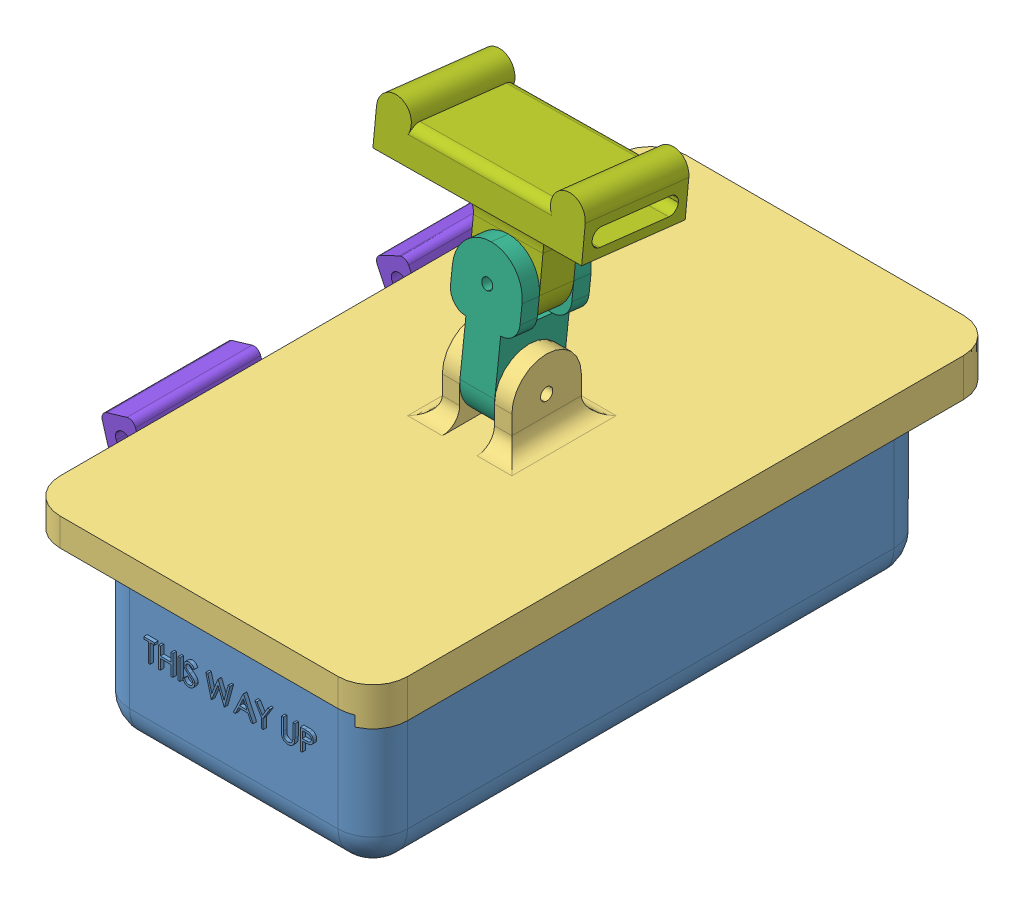
SolidWorks assembly Enclosure, configuration Default. Lengths in mm.
Overall size (141.75 176.14 228.6).
95 component instances, 26 part files, 36 mates.
Components (placement in the parent):
- Case-2: Case [Default] at (-101.6 0 -203.2) x (0 0 1) z (0 1 0) size (222.25 128.91 71.12)
- Battery Mockup-1: Battery Mockup [Default] at (-90.805 45.72 -177.165) x (0 0 1) z (-1 0 0) size (171.45 22.86 80.01)
- Lid-1: Lid [Default] at (12.7 73.66 12.7) x (-1 0 0) z (0 0 1) size (132.08 39.88 228.6)
- Camera Bracket-1: Camera Bracket [Default] at (-25.4 2.54 -66.675) x (0 0 -1) z (1 0 0) size (50.8 7.62 50.8)
- Separator-1: Separator [Default] at (-3.175 45.72 -3.175) x (0 -1 0) z (1 0 0) size (2.54 196.85 95.25)
- Cam V2.1 v1.step-1: Cam V2.1 v1.step [Default] at (-51.73 11.16 -89.4159) x (0 -1 0) z (1 0 0) size (6.48 24.01 25.01)
- RapberryPiZero.STEP-1: RapberryPiZero.STEP [Default] at (-102.4814 -13.0566 -128.6208) x (-1 0 0) z (0 0 -1) size (65 4.45 31.23)
  - Raspberry_pizero_PCB.STEP-1: Raspberry_pizero_PCB.STEP [Default] at (-51.2564 20.0966 13.0542) size (65 1 30)
  - Micro USB_input_female (short)-SMT.STEP-1: Micro USB_input_female (short)-SMT.STEP [Default] at (-42.3564 22.3216 26.5042) size (7.98 2.94 5.43)
  - Micro USB_input_female (short)-SMT.STEP-2: Micro USB_input_female (short)-SMT.STEP [Default] at (-29.7564 22.3216 26.5042) size (7.98 2.94 5.43)
  - 0204 - Capacitor.STEP-1: 0204 - Capacitor.STEP [Default] at (-62.4121 21.3466 11.2398) size (1 0.5 0.6)
  - 0204 - Capacitor.STEP-2: 0204 - Capacitor.STEP [Default] at (-62.4121 21.3466 12.2528) size (1 0.5 0.6)
  - 0204 - Capacitor.STEP-3: 0204 - Capacitor.STEP [Default] at (-61.8122 21.3466 13.3136) size (1 0.5 0.6)
  - 0204 - Capacitor.STEP-4: 0204 - Capacitor.STEP [Default] at (-61.8122 21.3466 14.2646) size (1 0.5 0.6)
  - 0204 - Capacitor.STEP-5: 0204 - Capacitor.STEP [Default] at (-61.8122 21.3466 15.241) size (1 0.5 0.6)
  - 0204 - Capacitor.STEP-6: 0204 - Capacitor.STEP [Default] at (-61.8122 21.3466 16.2144) size (1 0.5 0.6)
  - 0204 - Capacitor.STEP-7: 0204 - Capacitor.STEP [Default] at (-61.8122 21.3466 17.2416) size (1 0.5 0.6)
  - 0204 - Capacitor.STEP-8: 0204 - Capacitor.STEP [Default] at (-62.5919 21.3466 20.9695) size (1 0.5 0.6)
  - 0204 - Capacitor.STEP-9: 0204 - Capacitor.STEP [Default] at (-62.5919 21.3466 21.919) size (1 0.5 0.6)
  - 0204 - Capacitor.STEP-10: 0204 - Capacitor.STEP [Default] at (-60.4584 21.3466 22.3712) x (0 0 1) z (-1 0 0) size (1 0.5 0.6)
  - 0204 - Capacitor.STEP-11: 0204 - Capacitor.STEP [Default] at (-60.0807 21.3466 22.3712) x (0 0 -1) z (1 0 0) size (1 0.5 0.6)
  - 0204 - Capacitor.STEP-12: 0204 - Capacitor.STEP [Default] at (-59.0466 21.3466 22.3712) x (0 0 -1) z (1 0 0) size (1 0.5 0.6)
  - 0204 - Capacitor.STEP-13: 0204 - Capacitor.STEP [Default] at (-52.6496 21.3466 22.316) x (0 0 1) z (-1 0 0) size (1 0.5 0.6)
  - 0204 - Capacitor.STEP-14: 0204 - Capacitor.STEP [Default] at (-52.25 21.3466 22.316) x (0 0 -1) z (1 0 0) size (1 0.5 0.6)
  - 0204 - Capacitor.STEP-15: 0204 - Capacitor.STEP [Default] at (-51.2398 21.3466 22.316) x (0 0 -1) z (1 0 0) size (1 0.5 0.6)
  - 0204 - Capacitor.STEP-16: 0204 - Capacitor.STEP [Default] at (-49.1841 21.3466 22.316) x (0 0 -1) z (1 0 0) size (1 0.5 0.6)
  - 0204 - Capacitor.STEP-17: 0204 - Capacitor.STEP [Default] at (-48.1448 21.3466 22.316) x (0 0 -1) z (1 0 0) size (1 0.5 0.6)
  - 0204 - Capacitor.STEP-18: 0204 - Capacitor.STEP [Default] at (-46.475 21.3466 21.113) size (1 0.5 0.6)
  - 0204 - Capacitor.STEP-19: 0204 - Capacitor.STEP [Default] at (-45.7322 21.3466 20.0663) size (1 0.5 0.6)
  - 0204 - Capacitor.STEP-20: 0204 - Capacitor.STEP [Default] at (-45.7322 21.3466 19.0675) size (1 0.5 0.6)
  - 0204 - Capacitor.STEP-21: 0204 - Capacitor.STEP [Default] at (-45.7322 21.3466 18.1249) size (1 0.5 0.6)
  - 0204 - Capacitor.STEP-22: 0204 - Capacitor.STEP [Default] at (-45.7322 21.3466 17.1095) size (1 0.5 0.6)
  - 0204 - Capacitor.STEP-23: 0204 - Capacitor.STEP [Default] at (-46.3457 21.3466 16.1412) size (1 0.5 0.6)
  - 0204 - Capacitor.STEP-24: 0204 - Capacitor.STEP [Default] at (-46.3457 21.3466 15.1229) size (1 0.5 0.6)
  - 0204 - Capacitor.STEP-25: 0204 - Capacitor.STEP [Default] at (-46.3457 21.3466 14.0197) size (1 0.5 0.6)
  - 0204 - Capacitor.STEP-26: 0204 - Capacitor.STEP [Default] at (-46.3457 21.3466 12.9589) size (1 0.5 0.6)
  - 0204 - Capacitor.STEP-27: 0204 - Capacitor.STEP [Default] at (-43.6156 21.3466 13.1418) size (1 0.5 0.6)
  - 0204 - Capacitor.STEP-28: 0204 - Capacitor.STEP [Default] at (-43.6156 21.3466 10.1424) size (1 0.5 0.6)
  - 0204 - Capacitor.STEP-29: 0204 - Capacitor.STEP [Default] at (-48.9117 21.3466 7.6917) size (1 0.5 0.6)
  - 0204 - Capacitor.STEP-30: 0204 - Capacitor.STEP [Default] at (-55.4926 21.3466 7.2526) x (0 0 -1) z (1 0 0) size (1 0.5 0.6)
  - 0204 - Capacitor.STEP-31: 0204 - Capacitor.STEP [Default] at (-53.7932 21.3466 7.2526) x (0 0 1) z (-1 0 0) size (1 0.5 0.6)
  - 0204 - Capacitor.STEP-32: 0204 - Capacitor.STEP [Default] at (-59.8477 21.3466 7.2526) x (0 0 1) z (-1 0 0) size (1 0.5 0.6)
  - 0204- Resistor.STEP-1: 0204- Resistor.STEP [Default] at (-43.6109 21.4522 15.4193) x (-1 0 0) z (0 -1 0) size (0.99 0.51 0.36)
  - 0204- Resistor.STEP-2: 0204- Resistor.STEP [Default] at (-43.6109 21.4522 14.4127) x (-1 0 0) z (0 -1 0) size (0.99 0.51 0.36)
  - 0204- Resistor.STEP-3: 0204- Resistor.STEP [Default] at (-43.6109 21.4522 12.4047) x (-1 0 0) z (0 -1 0) size (0.99 0.51 0.36)
  - 0204- Resistor.STEP-4: 0204- Resistor.STEP [Default] at (-42.6936 21.4522 18.4076) x (-1 0 0) z (0 -1 0) size (0.99 0.51 0.36)
  - 0204- Resistor.STEP-5: 0204- Resistor.STEP [Default] at (-39.831 21.4522 18.1462) x (0 0 1) z (0 -1 0) size (0.99 0.51 0.36)
  - 0204- Resistor.STEP-6: 0204- Resistor.STEP [Default] at (-61.8169 21.4522 19.8533) x (-1 0 0) z (0 -1 0) size (0.99 0.51 0.36)
  - 0204- Resistor.STEP-7: 0204- Resistor.STEP [Default] at (-61.8169 21.4522 18.5178) x (-1 0 0) z (0 -1 0) size (0.99 0.51 0.36)
  - 0204- Resistor.STEP-8: 0204- Resistor.STEP [Default] at (-79.148 21.4522 17.7279) x (-1 0 0) z (0 -1 0) size (0.99 0.51 0.36)
  - 0204- Resistor.STEP-9: 0204- Resistor.STEP [Default] at (-56.0985 21.4522 7.2479) x (0 0 -1) z (0 -1 0) size (0.99 0.51 0.36)
  - 0204- Resistor.STEP-10: 0204- Resistor.STEP [Default] at (-28.0827 21.4522 9.5819) x (-1 0 0) z (0 -1 0) size (0.99 0.51 0.36)
  - 0204- Resistor.STEP-11: 0204- Resistor.STEP [Default] at (-21.8613 21.4522 20.9026) x (-1 0 0) z (0 -1 0) size (0.99 0.51 0.36)
  - CAP-0306.STEP-1: CAP-0306.STEP [Default] at (-45.8903 21.4966 8.7634) size (1.6 0.8 0.9)
  - CAP-0306.STEP-2: CAP-0306.STEP [Default] at (-82.0031 21.4966 19.0464) x (0 0 1) z (-1 0 0) size (1.6 0.8 0.9)
  - Raspberry_pizero_BCM2835 with VC4.STEP-1: Raspberry_pizero_BCM2835 with VC4.STEP [Default] at (-54.1608 21.5466 15.1238) x (1 0 0) z (0 0 -1) size (12 0.65 12)
  - Crystal 3.4x2.4mm.STEP-1: Crystal 3.4x2.4mm.STEP [Default] at (-65.3089 21.0966 19.2633) size (3.2 1 2.4)
  - 0204- Resistor.STEP-12: 0204- Resistor.STEP [Default] at (-68.4329 21.4522 5.4384) x (0 0 1) z (0 -1 0) size (0.99 0.51 0.36)
  - 0204- Resistor.STEP-13: 0204- Resistor.STEP [Default] at (-69.7255 21.4522 5.4384) x (0 0 1) z (0 -1 0) size (0.99 0.51 0.36)
  - 0204- Resistor.STEP-14: 0204- Resistor.STEP [Default] at (-65.0626 21.4522 16.5355) x (1 0 0) z (0 -1 0) size (0.99 0.51 0.36)
  - 32,768 Khz Crystal.STEP-1: 32,768 Khz Crystal.STEP [Default] at (-60.5154 21.1428 26.5473) x (0.999848 -0.017452 0) z (0 0 1) size (3.4 1.03 1.5)
  - 0805- Capacitor.STEP-1: 0805- Capacitor.STEP [Default] at (-51.9496 21.9966 5.2384) x (1 0 0) z (0 -1 0) size (2 1.26 0.91)
  - 0805- Capacitor.STEP-2: 0805- Capacitor.STEP [Default] at (-51.9496 21.9966 7.3589) x (1 0 0) z (0 -1 0) size (2 1.26 0.91)
  - 0805- Capacitor.STEP-3: 0805- Capacitor.STEP [Default] at (-37.009 21.9966 22.5384) x (0 0 -1) z (0 -1 0) size (2 1.26 0.91)
  - 0805- Capacitor.STEP-4: 0805- Capacitor.STEP [Default] at (-29.8247 21.9966 13.3538) x (0 0 1) z (0 -1 0) size (2 1.26 0.91)
  - 0805- Capacitor.STEP-5: 0805- Capacitor.STEP [Default] at (-27.9052 21.9966 13.3538) x (0 0 -1) z (0 -1 0) size (2 1.26 0.91)
  - 0805- Capacitor.STEP-6: 0805- Capacitor.STEP [Default] at (-22.8003 21.9966 13.3538) x (0 0 -1) z (0 -1 0) size (2 1.26 0.91)
  - 0805- Capacitor.STEP-7: 0805- Capacitor.STEP [Default] at (-20.9924 21.9966 13.3538) x (0 0 -1) z (0 -1 0) size (2 1.26 0.91)
  - 0204- Resistor.STEP-15: 0204- Resistor.STEP [Default] at (-48.8769 21.4522 23.8207) x (1 0 0) z (0 -1 0) size (0.99 0.51 0.36)
  - 0204- Resistor.STEP-16: 0204- Resistor.STEP [Default] at (-52.4165 21.4522 24.0419) x (1 0 0) z (0 -1 0) size (0.99 0.51 0.36)
  - 0204 - Capacitor.STEP-33: 0204 - Capacitor.STEP [Default] at (-47.1199 21.3466 23.926) x (0 0 1) z (-1 0 0) size (1 0.5 0.6)
  - 0204 - Capacitor Brown.STEP-1: 0204 - Capacitor Brown.STEP [Default] at (-57.5817 21.3466 26.803) size (1 0.5 0.6)
  - 0204 - Capacitor Brown.STEP-2: 0204 - Capacitor Brown.STEP [Default] at (-64.0312 21.3466 26.8794) size (1 0.5 0.6)
  - 0204 - Capacitor Brown.STEP-3: 0204 - Capacitor Brown.STEP [Default] at (-46.3457 21.3466 12.214) size (1 0.5 0.6)
  - 0204 - Capacitor Brown.STEP-4: 0204 - Capacitor Brown.STEP [Default] at (-46.3457 21.3466 11.0963) size (1 0.5 0.6)
  - 0204 - Capacitor Brown.STEP-5: 0204 - Capacitor Brown.STEP [Default] at (-46.3457 21.3466 10.1566) size (1 0.5 0.6)
  - 0204 - Capacitor Brown.STEP-6: 0204 - Capacitor Brown.STEP [Default] at (-43.6156 21.3466 11.1151) size (1 0.5 0.6)
  - 0204 - Capacitor Brown.STEP-7: 0204 - Capacitor Brown.STEP [Default] at (-28.0874 21.3466 10.3236) size (1 0.5 0.6)
  - 0204 - Capacitor Brown.STEP-8: 0204 - Capacitor Brown.STEP [Default] at (-80.6197 21.3466 20.6997) size (1 0.5 0.6)
  - 0204- Resistor.STEP-17: 0204- Resistor.STEP [Default] at (-78.9105 21.4522 21.1554) x (1 0 0) z (0 -1 0) size (0.99 0.51 0.36)
  - 6-Pin SOT.STEP-1: 6-Pin SOT.STEP [Default] at (-79.714 21.0966 19.2138) x (0 0 1) z (0 1 0) size (1.5 1.84 0.95)
  - micro sd molex.STEP-1: micro sd molex.STEP [Default] at (-74.7768 21.6766 -33.0961) x (0 0 1) z (0 1 0) size (11.95 11.4 1.45)
  - hdmi type C.STEP-1: hdmi type C.STEP [Default] at (-71.3564 22.9466 28.6542) size (12.9 4.05 7.7)
  - Voltage Regulator 3x3mm 12-Pin.STEP-1: Voltage Regulator 3x3mm 12-Pin.STEP [Default] at (-23.6842 21.0966 12.6105) x (1 0 0) z (0 1 0) size (3 4.1 1.2)
  - 1210 inductor.STEP-1: 1210 inductor.STEP [Default] at (-46.4963 21.0916 6.3909) x (0 0 1) z (0 1 0) size (3.26 2.79 0.75)
  - 1210 inductor.STEP-2: 1210 inductor.STEP [Default] at (-22.7405 21.0916 9.2394) x (1 0 0) z (0 1 0) size (3.26 2.79 0.75)
  - 1210 inductor.STEP-3: 1210 inductor.STEP [Default] at (-28.2854 21.0916 17.6682) x (1 0 0) z (0 1 0) size (3.26 2.79 0.75)
  - 0204 - Capacitor.STEP-34: 0204 - Capacitor.STEP [Default] at (-48.9117 21.3466 6.5273) size (1 0.5 0.6)
- HCSR501.step-1: HCSR501.step [Default] at (-50.8 6.08 -41.275) x (-1 0 0) z (0 -1 0) size (32 25 25.1)
- Latch-1: Latch [Default] at (-117.1107 62.675 -33.02) x (0.048133 -0.998841 0) z (0 0 1) size (36.83 11.74 35.56)
- Latch-2: Latch [Default] at (-118.5313 61.2626 -134.62) x (0.334291 -0.94247 0) z (0 0 1) size (36.83 11.74 35.56)
- Swivel-1: Swivel [Default] at (-57.15 86.8687 -101.6) x (0 0.993442 -0.114338) z (1 0 0) size (57.15 25.4 25.4)
- Mount-1: Mount [Default] at (-50.8 117.6845 -111.5386) x (-0.00983 0.993394 -0.114332) z (0 0.114338 0.993442) size (57.15 76.2 38.1)
- Hook-1: Hook [Default] at (-104.5164 49.2758 -129.54) x (-0.903606 -0.428364 0) z (0 0 -1) size (12.7 30.48 45.72)
- Hook-2: Hook [Default] at (-106.6984 47.961 -27.94) x (-0.958568 -0.284865 0) z (0 0 -1) size (12.7 30.48 45.72)
Mates (geometry in assembly coordinates):
- Distance1: distance = 2.54 mm anti-aligned: plane of Battery Mockup-1 through (-90.805 68.58 -5.715) normal (0 0 1); plane of Top_001-2 through (-98.425 2.54 -3.175) normal (0 0 -1)
- Coincident1: coincident anti-aligned: plane of Top_001-2 through (-98.425 71.12 -3.175) normal (0 1 0); plane of Bottom_001-1 through (0 71.12 0) normal (0 -1 0)
- Distance2: distance = 0.635 mm anti-aligned: plane of Bottom_001-1 through (-111.76 63.5 -200.66) normal (1 0 0); plane of Top_001-2 through (-111.125 71.12 -200.025) normal (-1 0 0)
- Distance3: distance = 0.635 mm anti-aligned: plane of Bottom_001-1 through (-2.54 63.5 -213.36) normal (0 0 1); plane of Top_001-2 through (-3.175 71.12 -212.725) normal (0 0 -1)
- Coincident4: coincident anti-aligned: plane of Top_001-2 through (-101.6 2.54 -203.2) normal (0 1 0); plane of Camera Bracket-1 through (-31.75 2.54 -111.125) normal (0 -1 0)
- Coincident5: coincident anti-aligned: plane of Top_001-2 through (-85.725 43.18 -187.325) normal (0 1 0); plane of Separator-1 through (-15.875 43.18 -15.875) normal (0 -1 0)
- Concentric3: concentric anti-aligned: cylinder of Top_001-2 through (-85.725 2.54 -15.875) axis (0 -1 0) radius 12.7; cylinder of Separator-1 through (-85.725 43.18 -15.875) axis (0 1 0) radius 12.7
- Concentric4: concentric anti-aligned: cylinder of Top_001-2 through (-15.875 2.54 -15.875) axis (0 -1 0) radius 12.7; cylinder of Separator-1 through (-15.875 43.18 -15.875) axis (0 1 0) radius 12.7
- Distance4: distance = 7.62 mm anti-aligned: plane of Battery Mockup-1 through (-10.795 68.58 -177.165) normal (1 0 0); plane of Top_001-2 through (-3.175 2.54 -200.025) normal (-1 0 0)
- Coincident7: coincident anti-aligned: plane of Battery Mockup-1 through (-90.805 45.72 -177.165) normal (0 -1 0); plane of Separator-1 through (-15.875 45.72 -15.875) normal (0 1 0)
- Concentric5: concentric aligned: cylinder of Top_001-2 through (-31.75 6.985 -73.025) axis (0 -1 0) radius 2; cylinder of Camera Bracket-1 through (-31.75 10.16 -73.025) axis (0 -1 0) radius 1.5
- Concentric6: concentric aligned: cylinder of Top_001-2 through (-69.85 6.985 -73.025) axis (0 -1 0) radius 2; cylinder of Camera Bracket-1 through (-69.85 10.16 -73.025) axis (0 -1 0) radius 1.5
- Concentric12: concentric anti-aligned: cylinder of Top_001-2 through (-50.8 6.35 -41.275) axis (0 -1 0) radius 12.065; cylinder of HCSR501.step-1 through (-50.8 -0.8505 -41.275) axis (0 1 0) radius 11.4228
- Parallel3: parallel anti-aligned: plane of Top_001-2 through (-3.175 2.54 -200.025) normal (-1 0 0); plane of HCSR501.step-1 through (-34.8 6.08 -28.775) normal (1 0 0)
- Coincident12: coincident anti-aligned: plane of Top_001-2 through (-43.815 5.08 -41.275) normal (0 1 0); plane of HCSR501.step-1 through (-51.2586 5.08 -41.0657) normal (0 -1 0)
- Concentric14: concentric anti-aligned: cylinder of Top_001-2 through (-113.03 57.15 9.525) axis (0 0 -1) radius 1.5; cylinder of Latch-1 through (-113.03 57.15 -68.58) axis (0 0 1) radius 1.5
- Coincident13: coincident anti-aligned: plane of Top_001-2 through (-119.38 63.5 -38.1) normal (0 0 1); plane of Latch-1 through (-109.4995 63.0418 -38.1) normal (0 0 -1)
- Concentric15: concentric anti-aligned: circle of Top_001-2; cylinder of Latch-2 through (-113.03 57.15 -170.18) axis (0 0 1) radius 1.5
- Coincident14: coincident anti-aligned: plane of Top_001-2 through (-119.38 63.5 -165.1) normal (0 0 -1); plane of Latch-2 through (-111.3497 63.8099 -165.1) normal (0 0 1)
- Concentric16: concentric anti-aligned: cylinder of Camera Bracket-1 through (-62.23 2.54 -86.9159) axis (0 1 0) radius 1; cylinder of Cam V2.1 v1.step-1 through (-62.23 11.16 -86.9159) axis (0 -1 0) radius 1
- Concentric17: concentric anti-aligned: cylinder of Camera Bracket-1 through (-62.23 2.54 -99.4159) axis (0 1 0) radius 1; cylinder of Cam V2.1 v1.step-1 through (-62.23 11.16 -99.4159) axis (0 -1 0) radius 1
- Coincident15: coincident anti-aligned: plane of Camera Bracket-1 through (-31.75 10.16 -111.125) normal (0 1 0); plane of Cam V2.1 v1.step-1 through (-51.73 10.16 -89.4159) normal (0 -1 0)
- Concentric18: concentric anti-aligned: cylinder of Bottom_001-1 through (-63.5 86.8687 -101.6) axis (1 0 0) radius 2.25; cylinder of Swivel-1 through (-44.45 86.8687 -101.6) axis (-1 0 0) radius 2.25
- Coincident16: coincident anti-aligned: plane of Bottom_001-1 through (-57.15 73.66 -114.3) normal (1 0 0); plane of Swivel-1 through (-57.15 86.8687 -101.6) normal (-1 0 0)
- Concentric19: concentric aligned: cylinder of Swivel-1 through (-50.8 119.8626 -92.6135) axis (0 -0.114338 -0.993442) radius 12.7; cylinder of Mount-1 through (-50.8 119.1366 -98.9219) axis (0 -0.114338 -0.993442) radius 12.7
- Coincident17: coincident anti-aligned: plane of Swivel-1 through (-63.5 131.7533 -100.374) normal (0 -0.114338 -0.993442); plane of Mount-1 through (-50.8 119.1366 -98.9219) normal (0 0.114338 0.993442)
- Concentric20: concentric aligned: cylinder of Latch-1 through (-112.7244 50.8074 -68.58) axis (0 0 1) radius 1.6; cylinder of Upper Latch-2 through (-112.7244 50.8074 -73.66) axis (0 0 1) radius 1.5
- Coincident18: coincident anti-aligned: plane of Latch-1 through (-109.4995 63.0418 -68.58) normal (0 0 -1); plane of Upper Latch-2 through (-94.5246 51.5788 -68.58) normal (0 0 1)
- Concentric21: concentric aligned: cylinder of Latch-2 through (-110.9073 51.1653 -170.18) axis (0 0 1) radius 1.6; cylinder of Upper Latch-1 through (-110.9073 51.1653 -175.26) axis (0 0 1) radius 1.5
- Coincident19: coincident anti-aligned: plane of Latch-2 through (-111.3497 63.8099 -134.62) normal (0 0 1); plane of Upper Latch-1 through (-93.0406 54.716 -134.62) normal (0 0 -1)
- Concentric22: concentric aligned: cylinder of Top_001-2 through (-80.225 7.04 -130.175) axis (0 -1 0) radius 2; cylinder of RapberryPiZero.STEP-1/Raspberry_pizero_PCB.STEP-1 through (-80.225 8.04 -130.175) axis (0 -1 0) radius 1.375
- Concentric23: concentric aligned: cylinder of Top_001-2 through (-22.225 7.04 -153.175) axis (0 -1 0) radius 2; cylinder of RapberryPiZero.STEP-1/Raspberry_pizero_PCB.STEP-1 through (-22.225 8.04 -153.175) axis (0 -1 0) radius 1.375
- Coincident20: coincident anti-aligned: plane of Top_001-2 through (-101.6 7.04 -203.2) normal (0 1 0); plane of RapberryPiZero.STEP-1/Raspberry_pizero_PCB.STEP-1 through (-21.725 7.04 -129.675) normal (0 -1 0)
- Coincident21: coincident anti-aligned: plane of Top_001-2 through (-101.6 0 -203.2) normal (0 -1 0)
- Coincident22: coincident aligned: plane of Top_001-2 through (0 63.5 -203.2) normal (1 0 0)
- Coincident23: coincident aligned: plane of Top_001-2 through (-101.6 63.5 0) normal (0 0 1)
